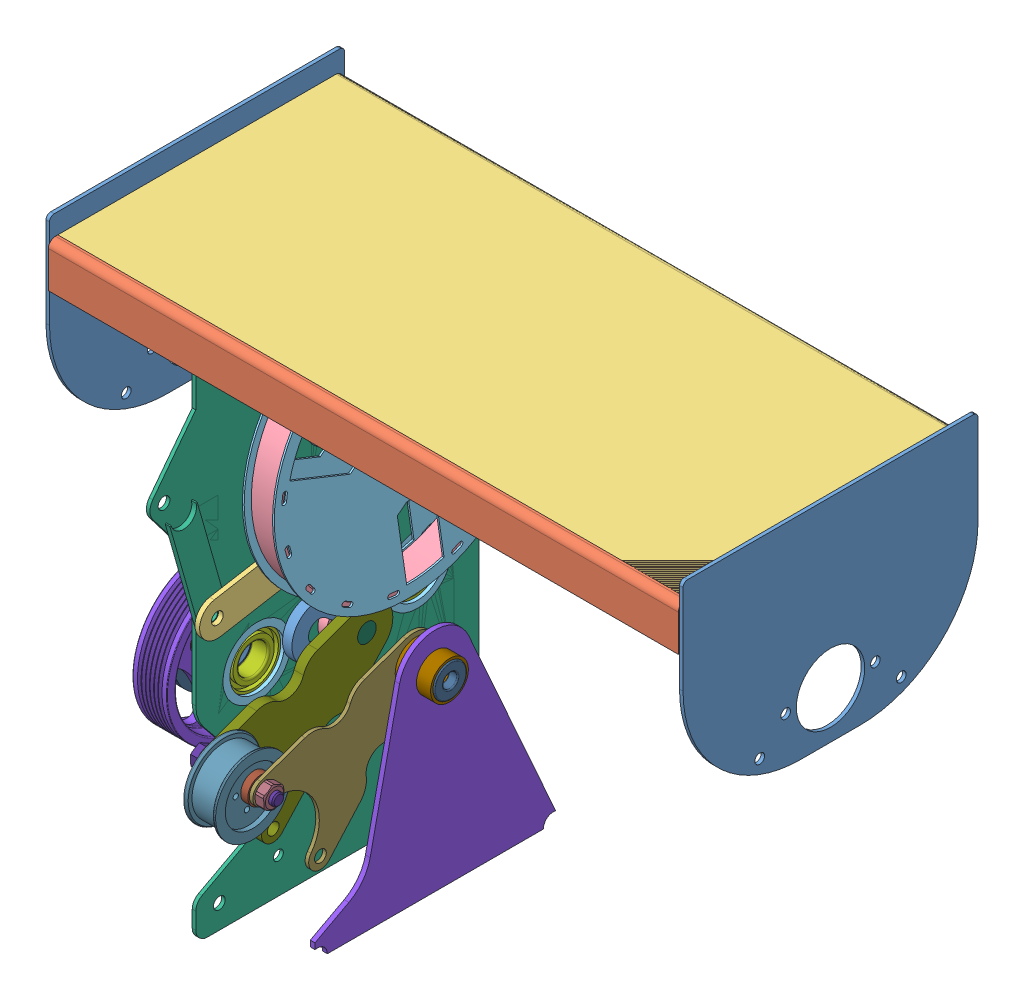
SolidWorks assembly Предсборка, configuration 00. Lengths in mm.
Overall size (840 484.48 323.03).
47 component instances, 31 part files, 58 mates.
Components (placement in the parent):
- Основной габарит коробки 540мм-1: Основной габарит коробки 540мм [00] at origin size (840 180 250)
- Верх коробки^Предсборка-1: Верх коробки^Предсборка [00] at origin size (540 180 251) (virtual)
  - 201026-ЩЕКА ДРК 09-3-6-1: 201026-ЩЕКА ДРК 09-3-6 [По умолчанию] at (-220 0 0) size (3 180 250)
  - 201026-ЩЕКА ДРК 09-3-6-2: 201026-ЩЕКА ДРК 09-3-6 [По умолчанию] at (317 0 0) size (3 180 250)
  - 201026-ПЛАНКА 540 09-3-3-1: 201026-ПЛАНКА 540 09-3-3 [По умолчанию] at (50 120 1.5) size (534 37 249) (hidden)
  - ТП002.01.02 - Планка 540-1: ТП002.01.02 - Планка 540 [--] at (-217 0 0) x (0 0 -1) z (1 0 0) size (246 37 534)
- Щека редуктора правая^Предсборка-1: Щека редуктора правая^Предсборка [00] at origin size (26.35 457 278.9) (virtual)
  - ТП.002.01.01.01.04 - ОБОЙМА 28-1: ТП.002.01.01.01.04 - ОБОЙМА 28 [По умолчанию] at (-90.55 -156 0) size (10.5 33 33)
  - Копия Деталь7^Щека редуктора правая_Предсборка-1: Копия Деталь7^Щека редуктора правая_Предсборка [00] at origin size (18 60 60) (virtual)
  - 201026-ЩЕКА 09-1: 201026-ЩЕКА 09 [По умолчанию] at (-101.05 0 0) size (3 457 278.9)
  - Копия Деталь5^Щека редуктора правая_Предсборка-1: Копия Деталь5^Щека редуктора правая_Предсборка [00] at origin size (16.7 24 24) (virtual)
  - Копия Деталь7^Щека редуктора правая_Предсборка-2: Копия Деталь7^Щека редуктора правая_Предсборка [00] at (0 -155.8076 -68) size (18 60 60) (virtual)
  - Копия Деталь7^Щека редуктора правая_Предсборка-3: Копия Деталь7^Щека редуктора правая_Предсборка [00] at (0 -155.8076 68) size (18 60 60) (virtual)
- Центральная опора^Предсборка-1: Центральная опора^Предсборка [00] at origin size (28 192 204) (virtual)
  - Опора качалок центральная-1: Опора качалок центральная [По умолчанию] at (-17 -156 0) size (4 192 204)
  - Копия Деталь2^Центральная опора_Предсборка-1: Копия Деталь2^Центральная опора_Предсборка [00] at origin size (28 36 36) (virtual)
- 12Х28Х8-1: 12Х28Х8 [По умолчанию] at (-2 -156 0) size (8 28 28)
- 12Х28Х8-2: 12Х28Х8 [По умолчанию] at (-24 -156 0) size (8 28 28)
- Внутреняя качалка^Предсборка-1: Внутреняя качалка^Предсборка [00] at origin size (12 172.94 186.38) (virtual)
  - ОСЬ 16Х26-1: ОСЬ 16Х26 [По умолчанию] at (-24 -156 0) x (0 0.875452 -0.483305) z (-1 0 0) size (16 16 12)
  - ДОПОПОРА-1: ДОПОПОРА [По умолчанию] at (-36 -156 0) x (0 -0.830865 -0.556474) z (1 0 0) size (105 154 3)
- М10 (ГОСТ 5915-70)-1: М10 (ГОСТ 5915-70) [По умолчанию] at (-28.8 -189.691 126.6774) x (1 0 0) z (0 0.830865 0.556474) size (8.4 18.6 17)
- 201026-Ролик натяжной-1: 201026-Ролик натяжной [По умолчанию] at (-42 -192.9187 131.4967) x (1 0 0) z (0 0.830865 0.556474) size (27 63.5 63.5)
- Внешняя качалка^Предсборка-1: Внешняя качалка^Предсборка [00] at origin size (25.05 174.05 188.04) (virtual)
  - Копия Деталь3^Внешняя качалка_Предсборка-1: Копия Деталь3^Внешняя качалка_Предсборка [00] at (-73 -156 0.0003) x (0 -0.830865 -0.556475) z (1 0 0) size (15.8 15.8 25.05) (virtual)
  - КАЧАЛКА-1: КАЧАЛКА [По умолчанию] at (-73 -156 0.0003) x (0 0.830865 0.556475) z (-1 0 0) size (105 156 8)
- М10х60(26)-1: М10х60(26) [По умолчанию] at (-81.6 -189.6911 126.6777) x (1 0 0) z (0 0.846343 0.532638) size (67.18 17.7 15.33)
- Толкатель^Предсборка-1: Толкатель^Предсборка [00] at origin size (24.9 162.62 128.36) (virtual)
  - Копия Деталь6^Толкатель_Предсборка-1: Копия Деталь6^Толкатель_Предсборка [00] at (-81.5 -167.4282 23.3668) x (0 -0.376884 -0.926261) z (1 0 0) size (15.8 15.8 24.9) (virtual)
  - РЫЧАГ 52-09-1: РЫЧАГ 52-09 [По умолчанию] at (-81.5 -167.4282 23.3668) x (0 0.376884 0.926261) z (-1 0 0) size (80.46 142.82 8)
- М8х20-1: М8х20 [По умолчанию] at (-90.1 -61.8345 -19.598) x (1 0 0) z (0 -0.570666 0.821182) size (26.05 14.38 12.45)
- ТЯГА 144-1: ТЯГА 144 [По умолчанию] at (-81.5 -61.8345 -19.598) x (1 0 0) z (0 -0.171718 0.985146) size (4 30 174)
- ШКИВ 215-1: ШКИВ 215 [По умолчанию] at (-39.5 0 0) size (27 294.96 294.96)
  - ОБОД ШКИВА 215-1: ОБОД ШКИВА 215 [По умолчанию] at origin size (24 215 215)
  - ЩЕКА ШКИВА 215-1: ЩЕКА ШКИВА 215 [По умолчанию] at (-25.5 0 0) x (1 0 0) z (0 -0.928794 0.370596) size (1.5 227 227)
  - ЩЕКА ШКИВА 215-2: ЩЕКА ШКИВА 215 [По умолчанию] x (1 0 0) z (0 -0.928794 0.370596) size (1.5 227 227)
- РЫЧАГ УПРАВЛЕНИЯ 2. 09-1: РЫЧАГ УПРАВЛЕНИЯ 2. 09 [По умолчанию] at (-81.5 0 146.9013) x (-1 0 0) z (0 -0.961799 -0.273758) size (4 24 102)
- 12Х28Х8-3: 12Х28Х8 [По умолчанию] at (-90.05 -156 0) size (8 28 28)
- Подшипник 180205-1: Подшипник 180205 [По умолчанию] at (-108.55 0 0) size (15 52 52)
- Подшипник 180205-2: Подшипник 180205 [По умолчанию] at (-108.55 -155.8076 -68) size (15 52 52)
- Подшипник 180205-5: Подшипник 180205 [По умолчанию] at (-108.55 -155.8076 68) size (15 52 52)
- Пирводной шкив в сборе^Предсборка-1: Пирводной шкив в сборе^Предсборка [00] at origin size (38 126.4 126.4) (virtual)
  - Шкив 2110-1: Шкив 2110 [По умолчанию] at (-111.35 -155.8076 68) x (-1 0 0) z (0 0 -1) size (29 126.4 126.4)
  - Болт М8 - 16мм-1: Болт М8 - 16мм [По умолчанию] at (-126.05 -143.3076 89.6506) x (-1 0 0) z (0 -0.924225 -0.381849) size (24 13 13)
  - Копия Деталь10^Пирводной шкив в сборе_Предсборка-1: Копия Деталь10^Пирводной шкив в сборе_Предсборка [00] at (0 0 68) size (33.3 72 72) (virtual)
- Деталь11^Предсборка-1: Деталь11^Предсборка [00] at (-42 -192.9187 131.4967) x (0 -0.830865 -0.556474) z (1 0 0) size (22.5 22.5 6) (virtual)
- Деталь12^Предсборка-1: Деталь12^Предсборка [00] at (-61 -192.9187 131.4967) x (0 0.830865 0.556474) z (-1 0 0) size (22.5 22.5 12) (virtual)
Mates (geometry in assembly coordinates):
- Концентричный15: concentric: cylinder of М8х20-1 through (-1090.1 -61.8345 -19.598) axis (-1 0 0) radius 4; cylinder of ТЯГА 144-1 through (-77.5 -61.8345 -19.598) axis (-1 0 0) radius 5
- Симметричный2: symmetric: plane of 201026-Ролик натяжной-1 through (-62.25 -177.6156 108.6479) normal (1 0 0); plane of 201026-Ролик натяжной-1 through (-40.75 -172.5307 101.0557) normal (-1 0 0); plane of ШКИВ 215-1/ОБОД ШКИВА 215-1 through (-51.5 0 0) normal (1 0 0)
- Концентричный17: concentric: cylinder of ТЯГА 144-1 through (-77.5 -86.5619 122.2631) axis (-1 0 0) radius 5; cylinder of РЫЧАГ УПРАВЛЕНИЯ 2. 09-1 through (-85.5 -86.5619 122.2631) axis (1 0 0) radius 4.25
- Совпадение25: coincident: plane of ТЯГА 144-1 through (-81.5 -61.8345 -19.598) normal (-1 0 0); plane of РЫЧАГ УПРАВЛЕНИЯ 2. 09-1 through (-81.5 0 146.9013) normal (1 0 0)
- На месте8: in place: plane of 201026-Ролик натяжной-1 through (-42 -192.9187 131.4967) normal (1 0 0); plane of ? through (-42 0 0) normal (1 0 0); moOrthogonalPlaneRef_w of 201026-Ролик натяжной-1 through (-42 -192.9187 131.4967) normal (1 0 0); plane of ? through (-42 0 0) normal (0 1 0); plane of 201026-Ролик натяжной-1 through (-42 -192.9187 131.4967) normal (1 0 0); plane of ? through (-42 0 0) normal (0 0 -1); plane of 201026-Ролик натяжной-1 through (-42 -192.9187 131.4967) normal (1 0 0); unknown of Деталь11^Предсборка-1
- Совпадение54: coincident: plane of 201026-Ролик натяжной-1; plane of Деталь11^Предсборка-1
- Совпадение55: coincident: moOrthogonalPlaneRef_w of 201026-Ролик натяжной-1 through (-42 -192.9187 131.4967) normal (0 0.556474 -0.830865); plane of Деталь11^Предсборка-1 through (-42 -192.9187 131.4967) normal (0 0.556474 -0.830865)
- Совпадение56: coincident: moOrthogonalPlaneRef_w of 201026-Ролик натяжной-1 through (-42 -192.9187 131.4967) normal (0 0.830865 0.556474); plane of Деталь11^Предсборка-1 through (-42 -192.9187 131.4967) normal (0 -0.830865 -0.556474)
- На месте9: in place: plane of 201026-Ролик натяжной-1 through (-61 -192.9187 131.4967) normal (-1 0 0); plane of ? through (-61 0 0) normal (-1 0 0); plane of 201026-Ролик натяжной-1 through (-61 -192.9187 131.4967) normal (-1 0 0); plane of ? through (-61 0 0) normal (0 1 0); plane of 201026-Ролик натяжной-1 through (-61 -192.9187 131.4967) normal (-1 0 0); plane of ? through (-61 0 0) normal (0 0 1); plane of 201026-Ролик натяжной-1 through (-61 -192.9187 131.4967) normal (-1 0 0); unknown of Деталь12^Предсборка-1
- Совпадение57: coincident: plane of 201026-Ролик натяжной-1; plane of Деталь12^Предсборка-1
- Совпадение58: coincident: moOrthogonalPlaneRef_w of 201026-Ролик натяжной-1 through (-61 -192.9187 131.4967) normal (0 0.556474 -0.830865); plane of Деталь12^Предсборка-1 through (-61 -192.9187 131.4967) normal (0 0.556474 -0.830865)
- Совпадение59: coincident: moOrthogonalPlaneRef_w of 201026-Ролик натяжной-1 through (-61 -192.9187 131.4967) normal (0 -0.830865 -0.556474); plane of Деталь12^Предсборка-1 through (-61 -192.9187 131.4967) normal (0 0.830865 0.556474)
- Концентричный144: concentric: cylinder of Подшипник 180205-5 through (-982.5417 -155.8076 68) axis (-1 0 0) radius 12.5; cylinder of Пирводной шкив в сборе^Предсборка-1/Шкив 2110-1 through (472.8014 -155.8076 68) axis (1 0 0) radius 14.75
- Параллельность4: parallel: line of Основной габарит коробки 540мм-1 through (-220 140 121) axis (0 0 -1); plane of Щека редуктора правая^Предсборка-1/201026-ЩЕКА 09-1 through (-98.05 120 -120) normal (0 1 0)
- Концентричный149: concentric: cylinder of Щека редуктора правая^Предсборка-1/201026-ЩЕКА 09-1 through (-98.05 0 0) axis (-1 0 0) radius 29; cylinder of ШКИВ 215-1/ЩЕКА ШКИВА 215-1 through (-63.5 0 0) axis (-1 0 0) radius 17.5
- Расстояние9: distance = 2.5 mm: plane of Щека редуктора правая^Предсборка-1/201026-ЩЕКА 09-1 through (-98.05 0 0) normal (1 0 0); plane of М8х20-1 through (-95.55 -61.8345 -19.598) normal (-1 0 0)
- Концентричный150: concentric: cylinder of Щека редуктора правая^Предсборка-1/201026-ЩЕКА 09-1 through (-98.05 0 146.9013) axis (-1 0 0) radius 5; cylinder of РЫЧАГ УПРАВЛЕНИЯ 2. 09-1 through (-85.5 0 146.9013) axis (1 0 0) radius 11
- Совпадение50: coincident: plane of Щека редуктора правая^Предсборка-1/201026-ЩЕКА 09-1 through (-98.05 0 0) normal (1 0 0); plane of 12Х28Х8-3 through (-98.05 -143 0) normal (-1 0 0)
- Концентричный151: concentric: cylinder of Щека редуктора правая^Предсборка-1/201026-ЩЕКА 09-1 through (-98.05 -156 0) axis (-1 0 0) radius 15; cylinder of 12Х28Х8-3 through (-90.05 -156 0) axis (1 0 0) radius 14
- Совпадение51: coincident: plane of Щека редуктора правая^Предсборка-1/201026-ЩЕКА 09-1 through (-101.05 0 0) normal (-1 0 0); plane of Подшипник 180205-1 through (-101.05 21 0) normal (1 0 0)
- Концентричный152: concentric: cylinder of Щека редуктора правая^Предсборка-1/201026-ЩЕКА 09-1 through (-98.05 0 0) axis (-1 0 0) radius 29; cylinder of Подшипник 180205-1 through (-982.5417 0 0) axis (-1 0 0) radius 26
- Параллельность5: parallel: plane of Щека редуктора правая^Предсборка-1/201026-ЩЕКА 09-1 through (-101.05 0 0) normal (-1 0 0); plane of Пирводной шкив в сборе^Предсборка-1/Шкив 2110-1 through (-125.05 -100.4076 68) normal (1 0 0)
- Совпадение52: coincident: plane of Щека редуктора правая^Предсборка-1/Копия Деталь7^Щека редуктора правая_Предсборка-2 through (-101.05 -132.8076 -68) normal (-1 0 0); plane of Подшипник 180205-2 through (-101.05 -134.8076 -68) normal (1 0 0)
- Концентричный153: concentric: cylinder of Щека редуктора правая^Предсборка-1/Копия Деталь7^Щека редуктора правая_Предсборка-2 through (-108.55 -155.8076 -68) axis (1 0 0) radius 26; cylinder of Подшипник 180205-2 through (-982.5417 -155.8076 -68) axis (-1 0 0) radius 26
- Совпадение53: coincident: plane of Щека редуктора правая^Предсборка-1/Копия Деталь7^Щека редуктора правая_Предсборка-3 through (-101.05 -132.8076 68) normal (-1 0 0); plane of Подшипник 180205-5 through (-101.05 -134.8076 68) normal (1 0 0)
- Концентричный154: concentric: cylinder of Щека редуктора правая^Предсборка-1/Копия Деталь7^Щека редуктора правая_Предсборка-3 through (-108.55 -155.8076 68) axis (1 0 0) radius 26; cylinder of Подшипник 180205-5 through (-982.5417 -155.8076 68) axis (-1 0 0) radius 26
- Расстояние10: distance = 2 mm: plane of Пирводной шкив в сборе^Предсборка-1/Болт М8 - 16мм-1 through (-118.05 -143.3076 89.6506) normal (1 0 0); plane of Щека редуктора правая^Предсборка-1/Копия Деталь7^Щека редуктора правая_Предсборка-3 through (-116.05 -129.8076 68) normal (-1 0 0)
- Совпадение54: coincident: line of Основной габарит коробки 540мм-1 through (-220 60 125) axis (0 1 0); line of Верх коробки^Предсборка-1/201026-ЩЕКА ДРК 09-3-6-1 through (-220 136 125) axis (0 -1 0)
- Совпадение55: coincident: line of Основной габарит коробки 540мм-1 through (-220 140 121) axis (0 0 -1); line of Верх коробки^Предсборка-1/201026-ЩЕКА ДРК 09-3-6-1 through (-220 140 -121) axis (0 0 1)
- Концентричный155: concentric: cylinder of Верх коробки^Предсборка-1/201026-ЩЕКА ДРК 09-3-6-1 through (-217 0 0) axis (-1 0 0) radius 29; cylinder of Щека редуктора правая^Предсборка-1/201026-ЩЕКА 09-1 through (-98.05 0 0) axis (-1 0 0) radius 29
- Совпадение56: coincident: line of Основной габарит коробки 540мм-1 through (320 136 125) axis (0 -1 0); line of Верх коробки^Предсборка-1/201026-ЩЕКА ДРК 09-3-6-2 through (320 136 125) axis (0 -1 0)
- Совпадение57: coincident: line of Основной габарит коробки 540мм-1 through (320 140 -121) axis (0 0 1); line of Верх коробки^Предсборка-1/201026-ЩЕКА ДРК 09-3-6-2 through (320 140 -121) axis (0 0 1)
- Совпадение58: coincident: plane of Верх коробки^Предсборка-1/201026-ПЛАНКА 540 09-3-3-1 through (-217 120 -120) normal (0 -1 0); plane of Щека редуктора правая^Предсборка-1/201026-ЩЕКА 09-1 through (-98.05 120 -120) normal (0 1 0)
- Совпадение59: coincident: plane of Верх коробки^Предсборка-1/201026-ПЛАНКА 540 09-3-3-1 through (-217 120 -120) normal (0 0 1); plane of Щека редуктора правая^Предсборка-1/201026-ЩЕКА 09-1 through (-98.05 -337 -120) normal (0 0 -1)
- Симметричный3: symmetric: plane of Центральная опора^Предсборка-1/Опора качалок центральная-1 through (-15 -156 0) normal (1 0 0); plane of Центральная опора^Предсборка-1/Опора качалок центральная-1 through (-19 -156 0) normal (-1 0 0); plane of assembly
- Концентричный156: concentric: cylinder of Центральная опора^Предсборка-1/Опора качалок центральная-1 through (-19 -156 0) axis (1 0 0) radius 16; cylinder of 12Х28Х8-1 through (-2 -156 0) axis (1 0 0) radius 14
- Расстояние11: distance = 5 mm: plane of Центральная опора^Предсборка-1/Опора качалок центральная-1 through (-15 -156 0) normal (1 0 0); plane of 12Х28Х8-1 through (-10 -143 0) normal (-1 0 0)
- Расстояние12: distance = 5 mm: plane of Центральная опора^Предсборка-1/Опора качалок центральная-1 through (-19 -156 0) normal (-1 0 0); plane of 12Х28Х8-2 through (-24 -149 0) normal (1 0 0)
- Концентричный157: concentric: cylinder of Центральная опора^Предсборка-1/Опора качалок центральная-1 through (-19 -156 0) axis (1 0 0) radius 16; cylinder of 12Х28Х8-2 through (-24 -156 0) axis (1 0 0) radius 14
- Концентричный158: concentric: cylinder of Щека редуктора правая^Предсборка-1/201026-ЩЕКА 09-1 through (-98.05 -317 100) axis (-1 0 0) radius 5; cylinder of Центральная опора^Предсборка-1/Опора качалок центральная-1 through (-19 -317 100) axis (1 0 0) radius 8.5
- Концентричный159: concentric: cylinder of Щека редуктора правая^Предсборка-1/201026-ЩЕКА 09-1 through (-98.05 -317 -100) axis (-1 0 0) radius 5; cylinder of Центральная опора^Предсборка-1/Опора качалок центральная-1 through (-19 -317 -100) axis (1 0 0) radius 8.5
- Концентричный160: concentric: cylinder of 12Х28Х8-2 through (-24 -156 0) axis (1 0 0) radius 6; cylinder of Внутреняя качалка^Предсборка-1/ОСЬ 16Х26-1 through (-32 -156 0) axis (1 0 0) radius 6
- Совпадение60: coincident: plane of 12Х28Х8-2 through (-32 -143 0) normal (-1 0 0); plane of Внутреняя качалка^Предсборка-1/ОСЬ 16Х26-1 through (-32 -156 0) normal (1 0 0)
- Совпадение61: coincident: plane of Внутреняя качалка^Предсборка-1/ДОПОПОРА-1 through (-33 -233.2332 115.3159) normal (1 0 0); plane of М10 (ГОСТ 5915-70)-1 through (-33 -186.9087 122.5231) normal (-1 0 0)
- Концентричный162: concentric: cylinder of Внутреняя качалка^Предсборка-1/ДОПОПОРА-1 through (-33 -189.691 126.6774) axis (-1 0 0) radius 5; cylinder of М10 (ГОСТ 5915-70)-1 through (-374.1781 -189.691 126.6774) axis (-1 0 0) radius 5
- Концентричный163: concentric: cylinder of Внутреняя качалка^Предсборка-1/ДОПОПОРА-1 through (-33 -189.691 126.6774) axis (-1 0 0) radius 5; cylinder of 201026-Ролик натяжной-1 through (-65 -189.6911 126.6777) axis (1 0 0) radius 5.25
- Расстояние13: distance = 2 mm: plane of Внутреняя качалка^Предсборка-1/ДОПОПОРА-1 through (-36 -233.2332 115.3159) normal (-1 0 0); plane of 201026-Ролик натяжной-1 through (-38 -179.8415 111.9713) normal (1 0 0)
- Концентричный164: concentric: cylinder of 201026-Ролик натяжной-1 through (-65 -189.6911 126.6777) axis (1 0 0) radius 5.25; cylinder of Внешняя качалка^Предсборка-1/КАЧАЛКА-1 through (-81 -189.6911 126.6777) axis (1 0 0) radius 5
- Расстояние14: distance = 8 mm: plane of Внешняя качалка^Предсборка-1/КАЧАЛКА-1 through (-73 -233.2332 115.3161) normal (1 0 0); plane of 201026-Ролик натяжной-1 through (-65 -179.8415 111.9713) normal (-1 0 0)
- Концентричный165: concentric: cylinder of Внешняя качалка^Предсборка-1/КАЧАЛКА-1 through (-81 -189.6911 126.6777) axis (1 0 0) radius 5; cylinder of М10х60(26)-1 through (-1081.6 -189.6911 126.6777) axis (-1 0 0) radius 5
- Совпадение62: coincident: plane of Внешняя качалка^Предсборка-1/КАЧАЛКА-1 through (-81 -233.2332 115.3161) normal (-1 0 0); plane of М10х60(26)-1 through (-81 -185.8091 120.5093) normal (1 0 0)
- Концентричный166: concentric: cylinder of Внешняя качалка^Предсборка-1/КАЧАЛКА-1 through (-73 -155.8076 68) axis (-1 0 0) radius 15; cylinder of Подшипник 180205-5 through (-982.5417 -155.8076 68) axis (-1 0 0) radius 12.5
- Концентричный167: concentric: cylinder of Внутреняя качалка^Предсборка-1/ОСЬ 16Х26-1 through (-36 -156 0) axis (1 0 0) radius 8; cylinder of Внешняя качалка^Предсборка-1/КАЧАЛКА-1 through (-81 -156 0.0003) axis (1 0 0) radius 7.9
- Концентричный168: concentric: cylinder of Толкатель^Предсборка-1/РЫЧАГ 52-09-1 through (-89.5 -61.8345 -19.598) axis (1 0 0) radius 4.25; cylinder of М8х20-1 through (-1090.1 -61.8345 -19.598) axis (-1 0 0) radius 4
- Совпадение63: coincident: plane of Толкатель^Предсборка-1/РЫЧАГ 52-09-1 through (-89.5 -155.9999 0.113) normal (-1 0 0); plane of М8х20-1 through (-89.5 -57.0813 -16.2948) normal (1 0 0)
- Совпадение64: coincident: plane of Толкатель^Предсборка-1/РЫЧАГ 52-09-1 through (-81.5 -155.9999 0.113) normal (1 0 0); plane of ТЯГА 144-1 through (-81.5 -61.8345 -19.598) normal (-1 0 0)
- Концентричный169: concentric: cylinder of Щека редуктора правая^Предсборка-1/201026-ЩЕКА 09-1 through (-98.05 -110 0) axis (-1 0 0) radius 10.5; cylinder of Толкатель^Предсборка-1/РЫЧАГ 52-09-1 through (-89.5 -110 0) axis (1 0 0) radius 7.9
- Расстояние16: distance = 0.5 mm: plane of Толкатель^Предсборка-1/РЫЧАГ 52-09-1 through (-81.5 -155.9999 0.113) normal (1 0 0); plane of Внешняя качалка^Предсборка-1/КАЧАЛКА-1 through (-81 -233.2332 115.3161) normal (-1 0 0)
